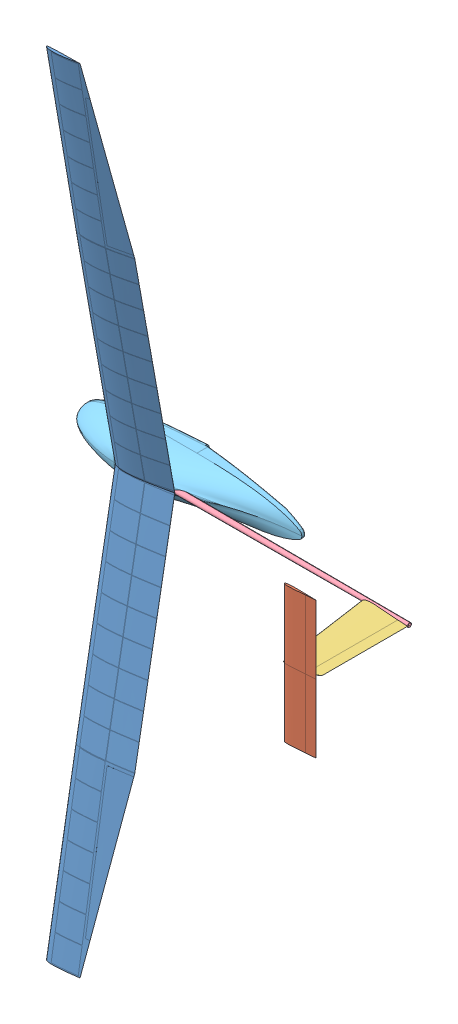
SolidWorks assembly seaway_mini, configuration Default. Lengths in mm.
Overall size (1788.65 4028.19 692.95).
5 component instances, 5 part files, 8 mates.
Components (placement in the parent):
- Wing^seaway_mini-1: Wing^seaway_mini [Default] at (0 0 26) size (282.01 4028.19 381.14) (virtual)
- HStab^seaway_mini-1: HStab^seaway_mini [Default] at origin size (154.52 695.63 11.86) (virtual)
- VStab^seaway_mini-1: VStab^seaway_mini [Default] at origin size (240.42 28.42 485.86) (virtual)
- Boom^seaway_mini-1: Boom^seaway_mini [Default] at origin size (1390.41 30 30) (virtual)
- pod_only-1: pod_only [Default] at (-78.9347 0 -145.8219) size (1117.92 199.12 247.21)
Mates (geometry in assembly coordinates):
- Coincident1: coincident aligned: plane of pod_only-1 through (-78.9347 0 -145.8219) normal (0 1 0)
- Parallel1: parallel aligned: plane of pod_only-1 through (-78.9347 0 -145.8219) normal (0 0 1)
- Distance1: distance = 391.3194 mm: point of pod_only-1
- Distance2: distance = 35 mm: unknown of pod_only-1
- Coincident4: coincident aligned: plane of Wing^seaway_mini-1 through (0 0 26) normal (0 1 0)
- Parallel2: parallel aligned: plane of Wing^seaway_mini-1 through (0 0 26) normal (0 0 1)
- Coincident6: coincident: unknown of Wing^seaway_mini-1
- Distance3: distance = 26 mm: plane of Wing^seaway_mini-1 through (0 0 26) normal (0 0 1)
